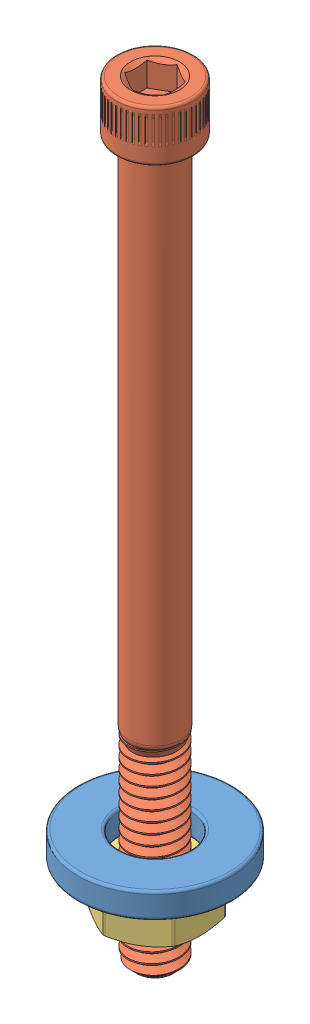
SolidWorks assembly ballscrew_mount_screw_assembly, configuration Default. Lengths in mm.
Overall size (26.53 95.84 26.53).
3 component instances, 3 part files, 6 mates.
Components (placement in the parent):
- 5-16x.75 oversize washer 91525A326_316 Stainless Steel Washer-1: 5-16x.75 oversize washer 91525A326_316 Stainless Steel Washer [91525A326] at (0 -76.0374 0) x (0.573642 0 -0.819106) z (0 -1 0) size (19.05 19.05 3.17)
- 1s4p20-3.5 socket head 91251A556_Black-Oxide Alloy Steel Socket Head Screw-1: 1s4p20-3.5 socket head 91251A556_Black-Oxide Alloy Steel Socket Head Screw [91251A556] at (0 -41.275 0) x (1 0 0) z (0 1 0) size (9.53 9.53 95.84)
- 1s4p20 nut 95462A029_Medium-Strength Steel Hex Nut-1: 1s4p20 nut 95462A029_Medium-Strength Steel Hex Nut [95462A029] at (0 -80.4031 0) x (1 0 0) z (0 1 0) size (11.11 12.75 6.32)
Mates (geometry in assembly coordinates):
- Concentric1: concentric anti-aligned: cylinder of 5-16x.75 oversize washer 91525A326_316 Stainless Steel Washer-1 through (0 -74.4499 0) axis (0 -1 0) radius 4.3688
- Distance1: distance aligned: plane of 5-16x.75 oversize washer 91525A326_316 Stainless Steel Washer-1 through (0 -74.4499 0) normal (0 1 0)
- Concentric5: concentric anti-aligned: cylinder of 1s4p20-3.5 socket head 91251A556_Black-Oxide Alloy Steel Socket Head Screw-1 through (0 9.1239 0) axis (0 -1 0) radius 3.2258
- Coincident5: coincident anti-aligned: circle of 5-16x.75 oversize washer 91525A326_316 Stainless Steel Washer-1; plane of 1s4p20 nut 95462A029_Medium-Strength Steel Hex Nut-1 through (0 -77.6249 0) normal (0 1 0)
- Concentric6: concentric aligned: cylinder of 5-16x.75 oversize washer 91525A326_316 Stainless Steel Washer-1 through (0 -74.4499 0) axis (0 -1 0) radius 4.3688; circle of 1s4p20 nut 95462A029_Medium-Strength Steel Hex Nut-1
- Coincident6: coincident anti-aligned: plane of 1s4p20-3.5 socket head 91251A556_Black-Oxide Alloy Steel Socket Head Screw-1 through (0 0 -3.175) normal (0 -1 0)
